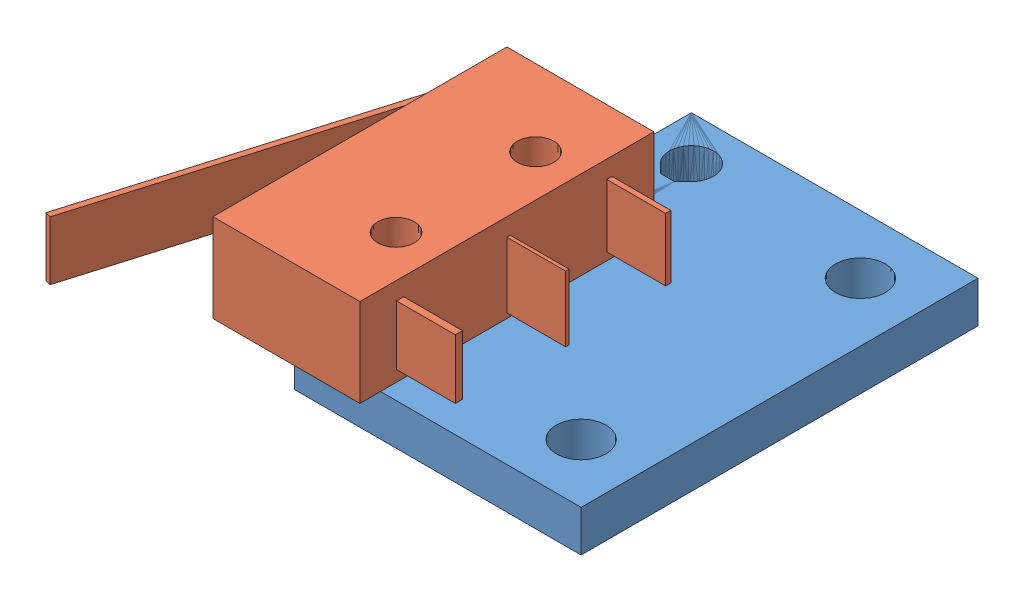
SolidWorks assembly subMontagem Xendstop, configuration Valor predeterminado. Lengths in mm.
Overall size (26.56 8.95 32.95).
2 component instances, 2 part files, 3 mates.
Components (placement in the parent):
- X-endstop-holder-1: X-endstop-holder [Valor predeterminado] at origin size (15.5 2.95 27)
- chave microswitch 3T kw11-3z 5A-1: chave microswitch 3T kw11-3z 5A [Valor predeterminado] at (3.66 12.2292 18.4) x (0 0 -1) z (1 0 0) size (24.55 6 20.91)
Mates (geometry in assembly coordinates):
- Concêntrico2: concentric anti-aligned: circle of X-endstop-holder-1; cylinder of chave microswitch 3T kw11-3z 5A-1 through (5.81 18.2292 13.6) axis (0 -1 0) radius 1.25
- Paralelo1: parallel aligned: plane of X-endstop-holder-1 through (2.81 12.2292 0) normal (-1 0 0); plane of chave microswitch 3T kw11-3z 5A-1 through (-1.34 18.2292 28.4) normal (-1 0 0)
- Coincidente6: coincident: line of X-endstop-holder-1 through (3.6538 12.2292 13.5) axis (0.062378 0 -0.998053); plane of chave microswitch 3T kw11-3z 5A-1 through (8.66 12.2292 8.4) normal (0 -1 0)
